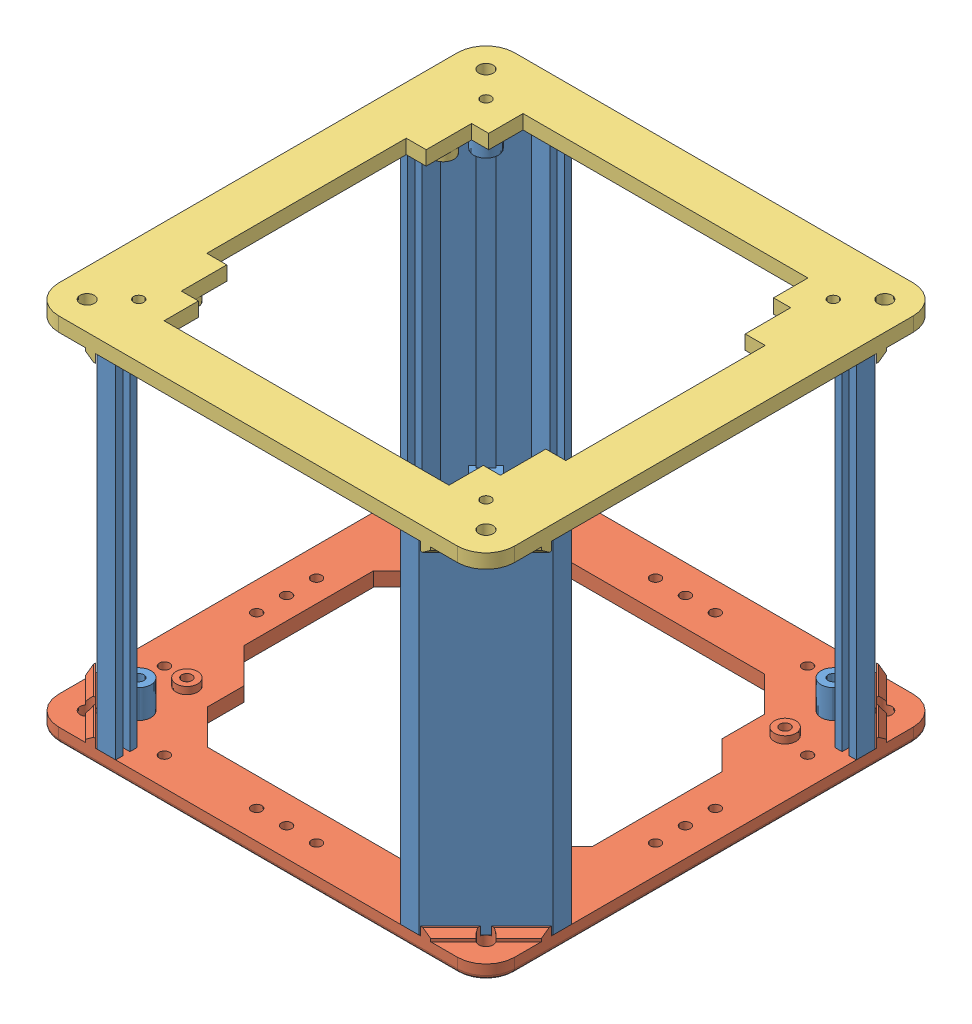
SolidWorks assembly SkeletonStructure, configuration Default. Lengths in mm.
Overall size (203.2 165.1 203.2).
6 component instances, 3 part files, 51 mates.
Components (placement in the parent):
- PillarV5-1: PillarV5 [Default] at (4.7406 88.2916 59.5274) x (0 0 -1) z (1 0 0) size (38.1 152.4 38.1)
- PillarV5-2: PillarV5 [Default] at (131.7406 88.2916 59.5274) size (38.1 152.4 38.1)
- PillarV5-3: PillarV5 [Default] at (131.7406 88.2916 186.5274) x (0 0 1) z (-1 0 0) size (38.1 152.4 38.1)
- PillarV5-4: PillarV5 [Default] at (4.7406 88.2916 186.5274) x (-1 0 0) z (0 0 -1) size (38.1 152.4 38.1)
- BaseTemplateV5-1: BaseTemplateV5 [Default] at (-33.3594 81.9416 224.6274) size (203.2 10.16 203.2)
- AltTopNoLidV5-1: AltTopNoLidV5 [Default] at (4.7406 240.6916 224.6274) x (0 0 -1) z (1 0 0) size (203.2 10.16 203.2)
Mates (geometry in assembly coordinates):
- Coincident26: coincident anti-aligned: plane of PillarV5-4 through (-9.1617 240.6916 200.4297) normal (0 1 0); plane of AltTopNoLidV5-1 through (157.1406 240.6916 211.9274) normal (0 -1 0)
- Coincident29: coincident aligned: plane of PillarV5-1 through (-33.3594 240.6916 51.3175) normal (-1 0 0); plane of AltTopNoLidV5-1 through (-33.3594 247.0416 211.9274) normal (-1 0 0)
- Coincident30: coincident aligned: plane of PillarV5-1 through (4.7406 240.6916 21.4274) normal (0 0 -1); plane of AltTopNoLidV5-1 through (-20.6594 247.0416 21.4274) normal (0 0 -1)
- Concentric5: concentric aligned: cylinder of Mock Rails-1 through (144.4406 240.6916 65.8774) axis (0 -1 0) radius 2.286; cylinder of Old PCB Power Shelf-1 through (144.4406 129.9792 65.8774) axis (0 -1 0) radius 2.286
- Concentric6: concentric aligned: cylinder of Mock Rails-3 through (-7.9594 240.6916 180.1774) axis (0 -1 0) radius 2.286; cylinder of Old PCB Power Shelf-1 through (-7.9594 129.9792 180.1774) axis (0 -1 0) radius 2.286
- Concentric7: concentric aligned: cylinder of Mock Rails-1 through (144.4406 240.6916 65.8774) axis (0 -1 0) radius 2.286; cylinder of Old PCB Power Shelf-3 through (144.4406 150.0562 65.8774) axis (0 -1 0) radius 2.286
- Concentric8: concentric aligned: cylinder of Mock Rails-3 through (-7.9594 240.6916 180.1774) axis (0 -1 0) radius 2.286; cylinder of Old PCB Power Shelf-3 through (-7.9594 150.0562 180.1774) axis (0 -1 0) radius 2.286
- Concentric9: concentric aligned: cylinder of Mock Rails-1 through (144.4406 240.6916 65.8774) axis (0 -1 0) radius 2.286; cylinder of Old PCB Power Shelf-4 through (144.4406 172.8458 65.8774) axis (0 -1 0) radius 2.286
- Concentric10: concentric aligned: cylinder of Mock Rails-3 through (-7.9594 240.6916 180.1774) axis (0 -1 0) radius 2.286; cylinder of Old PCB Power Shelf-4 through (-7.9594 172.8458 180.1774) axis (0 -1 0) radius 2.286
- Concentric11: concentric aligned: cylinder of Mock Rails-1 through (144.4406 240.6916 65.8774) axis (0 -1 0) radius 2.286; cylinder of Railshelf-2 through (144.4406 207.6328 65.8774) axis (0 -1 0) radius 2.286
- Concentric12: concentric aligned: cylinder of Mock Rails-3 through (-7.9594 240.6916 180.1774) axis (0 -1 0) radius 2.286; cylinder of Railshelf-2 through (-7.9594 207.6328 180.1774) axis (0 -1 0) radius 2.286
- Coincident44: coincident anti-aligned: plane of PillarV5-2 through (145.6429 88.2916 45.6251) normal (0 -1 0); plane of BaseTemplateV5-1 through (-33.3594 88.2916 224.6274) normal (0 1 0)
- Coincident45: coincident aligned: plane of PillarV5-2 through (139.9505 240.6916 21.4274) normal (0 0 -1); plane of BaseTemplateV5-1 through (-33.3594 88.2916 21.4274) normal (0 0 -1)
- Coincident46: coincident aligned: plane of PillarV5-2 through (169.8406 240.6916 59.5274) normal (1 0 0); plane of BaseTemplateV5-1 through (169.8406 88.2916 224.6274) normal (1 0 0)
- Coincident47: coincident anti-aligned: plane of PillarV5-3 through (145.6429 88.2916 200.4297) normal (0 -1 0); plane of BaseTemplateV5-1 through (-33.3594 88.2916 224.6274) normal (0 1 0)
- Coincident48: coincident aligned: plane of PillarV5-3 through (131.7406 240.6916 224.6274) normal (0 0 1); plane of BaseTemplateV5-1 through (-33.3594 88.2916 224.6274) normal (0 0 1)
- Coincident49: coincident aligned: plane of PillarV5-3 through (169.8406 240.6916 194.7373) normal (1 0 0); plane of BaseTemplateV5-1 through (169.8406 88.2916 224.6274) normal (1 0 0)
- Coincident50: coincident anti-aligned: plane of PillarV5-4 through (-9.1617 88.2916 200.4297) normal (0 -1 0); plane of BaseTemplateV5-1 through (-33.3594 88.2916 224.6274) normal (0 1 0)
- Coincident51: coincident aligned: plane of PillarV5-4 through (-3.4693 240.6916 224.6274) normal (0 0 1); plane of BaseTemplateV5-1 through (-33.3594 88.2916 224.6274) normal (0 0 1)
- Coincident52: coincident aligned: plane of PillarV5-4 through (-33.3594 240.6916 186.5274) normal (-1 0 0); plane of BaseTemplateV5-1 through (-33.3594 88.2916 224.6274) normal (-1 0 0)
- Coincident53: coincident anti-aligned: plane of PillarV5-1 through (-9.1617 88.2916 45.6251) normal (0 -1 0); plane of BaseTemplateV5-1 through (-33.3594 88.2916 224.6274) normal (0 1 0)
- Coincident54: coincident aligned: plane of PillarV5-1 through (-33.3594 240.6916 51.3175) normal (-1 0 0); plane of BaseTemplateV5-1 through (-33.3594 88.2916 224.6274) normal (-1 0 0)
- Coincident55: coincident aligned: plane of PillarV5-1 through (4.7406 240.6916 21.4274) normal (0 0 -1); plane of BaseTemplateV5-1 through (-33.3594 88.2916 21.4274) normal (0 0 -1)
- Coincident57: coincident anti-aligned: plane of Mock Rails-2 through (-7.9594 88.2916 65.8774) normal (0 -1 0); plane of BaseTemplateV5-1 through (-33.3594 88.2916 224.6274) normal (0 1 0)
- Coincident58: coincident anti-aligned: plane of Mock Rails-3 through (-7.9594 88.2916 180.1774) normal (0 -1 0); plane of BaseTemplateV5-1 through (-33.3594 88.2916 224.6274) normal (0 1 0)
- Coincident59: coincident anti-aligned: plane of Mock Rails-4 through (144.4406 88.2916 180.1774) normal (0 -1 0); plane of BaseTemplateV5-1 through (-33.3594 88.2916 224.6274) normal (0 1 0)
- Concentric20: concentric aligned: cylinder of Mock Rails-4 through (144.4406 240.6916 180.1774) axis (0 -1 0) radius 2.286; cylinder of BaseTemplateV5-1 through (144.4406 91.4666 180.1774) axis (0 -1 0) radius 2.286
- Concentric21: concentric aligned: cylinder of Mock Rails-2 through (-7.9594 240.6916 65.8774) axis (0 -1 0) radius 2.286; cylinder of BaseTemplateV5-1 through (-7.9594 91.4666 65.8774) axis (0 -1 0) radius 2.286
- Coincident60: coincident anti-aligned: plane of Mock Rails-1 through (144.4406 88.2916 65.8774) normal (0 -1 0); plane of BaseTemplateV5-1 through (-33.3594 88.2916 224.6274) normal (0 1 0)
- Concentric22: concentric aligned: cylinder of Mock Rails-3 through (-7.9594 240.6916 180.1774) axis (0 -1 0) radius 2.286; cylinder of BaseTemplateV5-1 through (-7.9594 91.4666 180.1774) axis (0 -1 0) radius 2.286
- Concentric23: concentric aligned: cylinder of Mock Rails-1 through (144.4406 240.6916 65.8774) axis (0 -1 0) radius 2.286; cylinder of BaseTemplateV5-1 through (144.4406 91.4666 65.8774) axis (0 -1 0) radius 2.286
- Coincident67: coincident anti-aligned: plane of BaseTemplateV5-1 through (-33.3594 88.2916 224.6274) normal (0 1 0); plane of FrontWallKeyV4-2 through (-1.5364 88.2916 214.9024) normal (0 -1 0)
- Concentric24: concentric anti-aligned: cylinder of BaseTemplateV5-1 through (122.7236 81.9416 211.9274) axis (0 1 0) radius 2.286; cylinder of FrontWallKeyV4-2 through (122.7236 100.9916 211.9274) axis (0 -1 0) radius 2.286
- Parallel4: parallel aligned: plane of BaseTemplateV5-1 through (-33.3594 88.2916 224.6274) normal (0 0 1); plane of FrontWallKeyV4-2 through (-1.5364 240.6916 221.2524) normal (0 0 1)
- Coincident71: coincident anti-aligned: plane of FrontWallKeyV4-2 through (-1.5364 240.6916 221.2524) normal (0 0 1); plane of LockBoltLoopV4-2 through (55.5136 225.4516 221.2524) normal (0 0 -1)
- Concentric26: concentric anti-aligned: cylinder of FrontWallKeyV4-2 through (77.8656 233.0716 221.2524) axis (0 0 -1) radius 2.286; cylinder of LockBoltLoopV4-2 through (77.8656 233.0716 221.2524) axis (0 0 1) radius 2.286
- Concentric27: concentric aligned: cylinder of LockBoltLoopV4-2 through (68.2136 240.6916 230.3964) axis (0 -1 0) radius 3.175; cylinder of lidV5-2 through (68.2136 246.8416 230.3964) axis (0 -1 0) radius 3.175
- Coincident80: coincident anti-aligned: plane of BaseTemplateV5-1 through (-33.3594 88.2916 224.6274) normal (0 1 0); plane of GoPro Mount 2-1 through (77.7656 88.2916 43.6524) normal (0 -1 0)
- Concentric30: concentric anti-aligned: cylinder of BaseTemplateV5-1 through (81.5756 81.9416 34.1274) axis (0 1 0) radius 2.286; cylinder of GoPro Mount 2-1 through (81.5756 90.8316 34.1274) axis (0 -1 0) radius 2.286
- Concentric31: concentric anti-aligned: cylinder of BaseTemplateV5-1 through (54.9056 81.9416 34.1274) axis (0 1 0) radius 2.286; cylinder of GoPro Mount 2-1 through (54.9056 90.8316 34.1274) axis (0 -1 0) radius 2.286
- Coincident81: coincident anti-aligned: plane of GoPro Mount 2-1 through (72.7406 112.6416 26.6274) normal (-1 0 0); plane of GoProExtension-1 through (72.7406 114.2373 39.9089) normal (1 0 0)
- Concentric32: concentric anti-aligned: cylinder of GoPro Mount 2-1 through (58.7156 105.1416 34.1274) axis (1 0 0) radius 2.525; cylinder of GoProExtension-1 through (75.7406 105.1416 34.1274) axis (-1 0 0) radius 2.525
- Concentric34: concentric aligned: cylinder of BaseTemplateV5-1 through (157.1406 88.2916 34.1274) axis (0 -1 0) radius 3.175; cylinder of Straw-4 through (157.1406 247.0416 34.1274) axis (0 -1 0) radius 2.794
- Coincident84: coincident anti-aligned: plane of BaseTemplateV5-1 through (-33.3594 88.2916 224.6274) normal (0 1 0); plane of Straw-4 through (157.1406 88.2916 34.1274) normal (0 -1 0)
- Parallel9: parallel anti-aligned: plane of BaseTemplateV5-1 through (145.202 92.1016 21.4274) normal (0.707107 0 -0.707107); plane of Straw-4 through (154.8567 89.5616 30.7659) normal (-0.707107 0 0.707107)
- Coincident90: coincident anti-aligned: plane of Old PCB Power Shelf-3 through (93.6406 150.0562 201.7674) normal (0 0 1); plane of BatteryHolder-1 through (-233.5482 -62.9224 201.7674) normal (0 0 -1)
- Coincident92: coincident anti-aligned: plane of BatteryHolder-1 through (-231.0082 -62.9224 204.3074) normal (0 0 1); plane of ICR18650 4400mAh Battery-1 through (-231.0082 -132.2644 204.3074) normal (0 0 -1)
- Coincident93: coincident anti-aligned: plane of BatteryHolder-1 through (-231.0082 -62.9224 204.3074) normal (1 0 0); plane of ICR18650 4400mAh Battery-1 through (-231.0082 -132.2644 222.3414) normal (-1 0 0)
- Coincident94: coincident anti-aligned: plane of BatteryHolder-1 through (-231.0082 -132.2644 204.3074) normal (0 1 0); plane of ICR18650 4400mAh Battery-1 through (-231.0082 -132.2644 222.3414) normal (0 -1 0)
- Concentric38: concentric aligned: cylinder of Mock Rails-1 through (144.4406 240.6916 65.8774) axis (0 -1 0) radius 2.286; cylinder of Power Shelf Layout Visualization-1/Old PCB Power Shelf-1 through (144.4406 96.6341 65.8774) axis (0 -1 0) radius 2.286
- Concentric39: concentric aligned: cylinder of Mock Rails-2 through (-7.9594 240.6916 65.8774) axis (0 -1 0) radius 2.286; cylinder of Power Shelf Layout Visualization-1/Old PCB Power Shelf-1 through (-7.9594 96.6341 65.8774) axis (0 -1 0) radius 2.286
